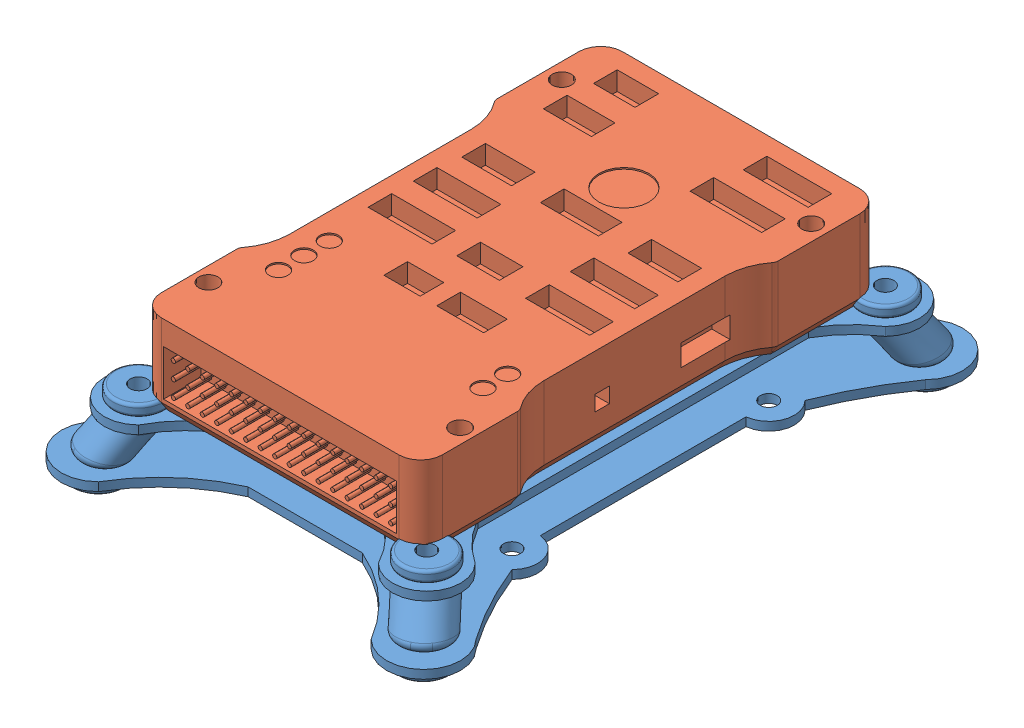
SolidWorks assembly damped pixhawk, configuration Default. Lengths in mm.
Overall size (70 26.23 101).
2 component instances, 2 part files, 2 mates.
Components (placement in the parent):
- base_pixhawk-1: base_pixhawk [Predeterminado] at (29.447 45.9195 87.309) size (70 13.5 101)
- FCU-1: FCU [Default] at (19.7246 57.2159 87.8047) size (58.89 14.99 80.82)
Mates (geometry in assembly coordinates):
- Coincident1: coincident anti-aligned: plane of base_pixhawk-1 through (16.1724 57.2159 33.5688) normal (0 1 0); plane of FCU-1 through (-3.6307 57.2159 111.1981) normal (0 -1 0)
- Lock1: lock: unknown of base_pixhawk-1; unknown of FCU-1
